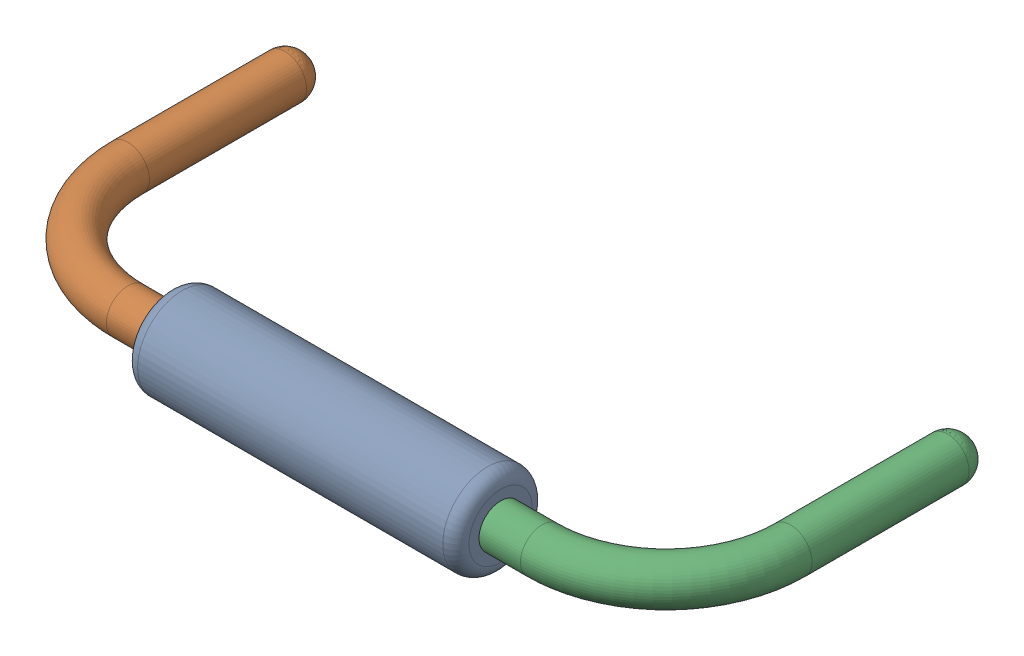
SolidWorks assembly R1, configuration Défaut. Lengths in mm.
Overall size (10.82 1.37 5.33).
4 component instances, 3 part files, 0 mates.
Components (placement in the parent):
- Open CASCADE STEP translator 6.8 1.10.1-1: Open CASCADE STEP translator 6.8 1.10.1 [Défaut] at origin size (10.82 1.37 5.33)
  - Body_1_7-1: Body_1_7 [Défaut] at origin size (5.08 1.37 1.37)
  - Pin_1_4-1: Pin_1_4 [Défaut] at origin size (3.2 0.66 4.98)
  - Pin_2_4-1: Pin_2_4 [Défaut] at (20.32 0 0) x (-1 0 0) z (0 0 1) size (3.2 0.66 4.98)
